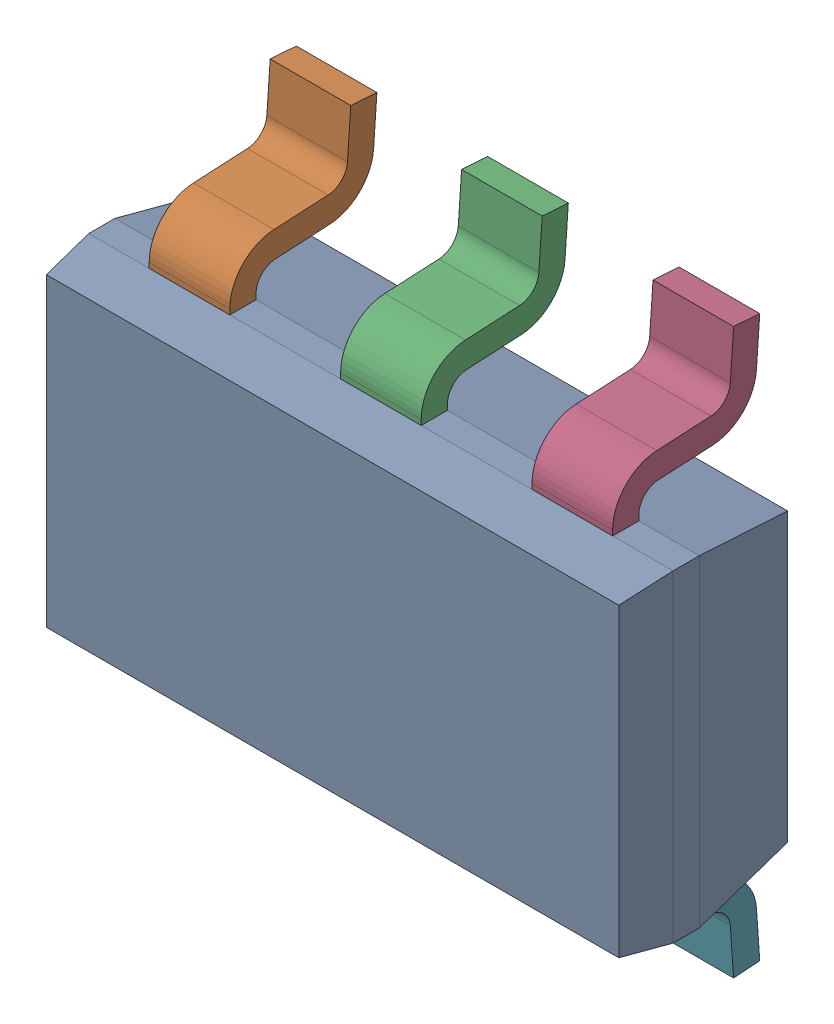
SolidWorks assembly U4, configuration ﾃﾞﾌｫﾙﾄ. Lengths in mm.
Overall size (2.9 2.8 0.97).
8 component instances, 2 part files, 0 mates.
Components (placement in the parent):
- DDC0006A-1: DDC0006A [ﾃﾞﾌｫﾙﾄ] at (33.655 22.5425 0) x (0 1 0) z (0 0 1) size (2.8 2.9 0.97)
  - BODY-SOT-1: BODY-SOT [ﾃﾞﾌｫﾙﾄ] at (0 0 0.73) x (0 1 0) z (1 0 0) size (2.9 0.87 1.6)
  - LEAD-SOT-1: LEAD-SOT [ﾃﾞﾌｫﾙﾄ] at (0.9409 0.95 0.25) x (0 1 0) z (1 0 0) size (0.4 0.73 0.6)
  - LEAD-SOT-2: LEAD-SOT [ﾃﾞﾌｫﾙﾄ] at (0.9409 0 0.25) x (0 1 0) z (1 0 0) size (0.4 0.73 0.6)
  - LEAD-SOT-3: LEAD-SOT [ﾃﾞﾌｫﾙﾄ] at (0.9409 -0.95 0.25) x (0 1 0) z (1 0 0) size (0.4 0.73 0.6)
  - LEAD-SOT-4: LEAD-SOT [ﾃﾞﾌｫﾙﾄ] at (-0.9409 0.95 0.25) x (0 -1 0) z (-1 0 0) size (0.4 0.73 0.6)
  - LEAD-SOT-5: LEAD-SOT [ﾃﾞﾌｫﾙﾄ] at (-0.9409 0 0.25) x (0 -1 0) z (-1 0 0) size (0.4 0.73 0.6)
  - LEAD-SOT-6: LEAD-SOT [ﾃﾞﾌｫﾙﾄ] at (-0.9409 -0.95 0.25) x (0 -1 0) z (-1 0 0) size (0.4 0.73 0.6)
